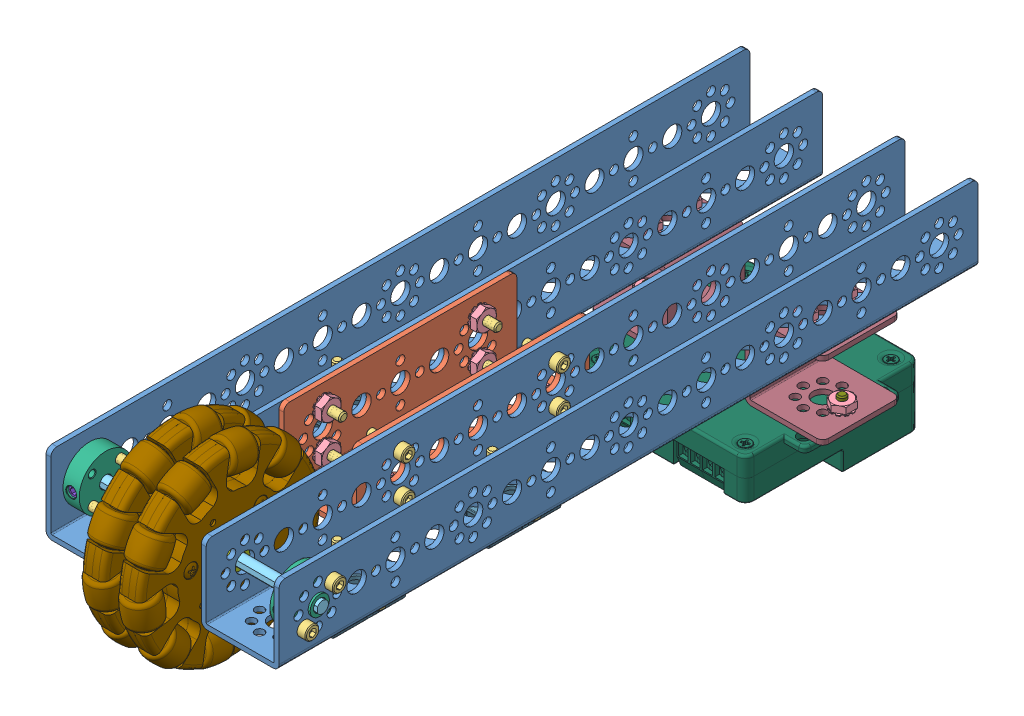
SolidWorks assembly Mantis step 4, configuration Default. Lengths in mm.
Overall size (103.01 112.11 310.85).
75 component instances, 16 part files, 198 mates.
Components (placement in the parent):
- Channel 288mm-1: Channel 288mm [Default] at (-32 0 0) size (32 32 288)
- Channel 288mm-2: Channel 288mm [Default] at (32 0 0) size (32 32 288)
- Channel 96mm-1: Channel 96mm [Default] at (0 0 32) size (32 32 96)
- Screw SHCS 6-32 x 0.5-7: Screw SHCS 6-32 x 0.5 [PreviewCfg] at (-21.5052 24 64) x (1 0 0) z (0 -1 0) size (16.21 5.74 5.74)
- Screw SHCS 6-32 x 0.5-8: Screw SHCS 6-32 x 0.5 [PreviewCfg] at (-21.5052 8 64) size (16.21 5.74 5.74)
- Screw SHCS 6-32 x 0.5-9: Screw SHCS 6-32 x 0.5 [PreviewCfg] at (-21.5052 8 0) x (1 0 0) z (0 0 -1) size (16.21 5.74 5.74)
- Screw SHCS 6-32 x 0.5-10: Screw SHCS 6-32 x 0.5 [PreviewCfg] at (-21.5052 24 0) x (1 0 0) z (0 0 -1) size (16.21 5.74 5.74)
- Nut Hex 6-32 KEP lock-1: Nut Hex 6-32 KEP lock [90675A007] at (-11.8172 8 0) x (0 0 -1) z (0 -1 0) size (8.74 3.59 9.17)
- Nut Hex 6-32 KEP lock-2: Nut Hex 6-32 KEP lock [90675A007] at (-11.8172 8 64) x (0 0 -1) z (0 -1 0) size (8.74 3.59 9.17)
- Nut Hex 6-32 KEP lock-3: Nut Hex 6-32 KEP lock [90675A007] at (-11.8172 24 64) x (0 0 -1) z (0 -1 0) size (8.74 3.59 9.17)
- Nut Hex 6-32 KEP lock-4: Nut Hex 6-32 KEP lock [90675A007] at (-11.8172 24 0) x (0 0 -1) z (0 -1 0) size (8.74 3.59 9.17)
- Screw SHCS 6-32 x 0.5-11: Screw SHCS 6-32 x 0.5 [PreviewCfg] at (21.5052 8 64) x (-1 0 0) z (0 0 -1) size (16.21 5.74 5.74)
- Screw SHCS 6-32 x 0.5-12: Screw SHCS 6-32 x 0.5 [PreviewCfg] at (21.5052 8 0) x (-1 0 0) z (0 0 -1) size (16.21 5.74 5.74)
- Screw SHCS 6-32 x 0.5-13: Screw SHCS 6-32 x 0.5 [PreviewCfg] at (21.5052 24 64) x (-1 0 0) z (0 0 -1) size (16.21 5.74 5.74)
- Screw SHCS 6-32 x 0.5-14: Screw SHCS 6-32 x 0.5 [PreviewCfg] at (21.5052 24 0) x (-1 0 0) z (0 0 -1) size (16.21 5.74 5.74)
- Nut Hex 6-32 KEP lock-5: Nut Hex 6-32 KEP lock [90675A007] at (11.8172 8 0) x (0 1 0) z (0 0 1) size (8.74 3.59 9.17)
- Nut Hex 6-32 KEP lock-6: Nut Hex 6-32 KEP lock [90675A007] at (11.8172 24 0) x (0 1 0) z (0 0 1) size (8.74 3.59 9.17)
- Nut Hex 6-32 KEP lock-7: Nut Hex 6-32 KEP lock [90675A007] at (11.8172 8 64) x (0 1 0) z (0 0 1) size (8.74 3.59 9.17)
- Nut Hex 6-32 KEP lock-8: Nut Hex 6-32 KEP lock [90675A007] at (11.8172 24 64) x (0 1 0) z (0 0 1) size (8.74 3.59 9.17)
- Axle D-shaft-1: Axle D-shaft [Default] at (0 16 128) x (0 1 0.000729) z (1 0 0) size (4.73 4.46 100)
- Hub axle shaft-1: Hub axle shaft [Default] at (46 16 128) x (0 0.707107 -0.707107) z (1 0 0) size (22 22 9.5)
- Hub axle shaft-2: Hub axle shaft [Default] at (-46 16 128) x (0 -0.707107 -0.707107) z (-1 0 0) size (22 22 9.5)
- Nylon spacer small-1: Nylon spacer small [Default] at (12.9 16 128) x (0 0 1) z (-1 0 0) size (9.5 9.5 3.1)
- Nylon spacer small-2: Nylon spacer small [Default] at (-16 16 128) x (0 0 1) z (-1 0 0) size (9.5 9.5 3.1)
- Screw SHCS 6-32 x 0.5-5: Screw SHCS 6-32 x 0.5 [PreviewCfg] at (-51.5052 10.3431 133.6569) size (16.21 5.74 5.74)
- Screw SHCS 6-32 x 0.5-4: Screw SHCS 6-32 x 0.5 [PreviewCfg] at (-51.5052 21.6569 122.3431) size (16.21 5.74 5.74)
- Screw SHCS 6-32 x 0.5-3: Screw SHCS 6-32 x 0.5 [PreviewCfg] at (51.5052 21.6569 122.3431) x (-1 0 0) z (0 0 -1) size (16.21 5.74 5.74)
- Screw SHCS 6-32 x 0.5-2: Screw SHCS 6-32 x 0.5 [PreviewCfg] at (51.5052 10.3431 133.6569) x (-1 0 0) z (0 0 -1) size (16.21 5.74 5.74)
- Screw SET 10-32 x 0.3125-2: Screw SET 10-32 x 0.3125 [PreviewCfg] at (42.6484 15.9927 138.0375) x (0 0.000729 -1) z (-1 0 0) size (7.94 4.83 4.83)
- Screw SET 10-32 x 0.3125-3: Screw SET 10-32 x 0.3125 [PreviewCfg] at (-42.6484 16.0073 138.0375) x (0 -0.000729 -1) z (1 0 0) size (7.94 4.83 4.83)
- Omni dual wheel spinner-1: Omni dual wheel spinner [Default] at (6.4355 15.7951 126.2756) x (0 0 1) z (0 -1 0) size (77.7 28.71 77.72)
  - 3-inch omni single wheel part-1: 3-inch omni single wheel part [Default] at (8.7963 -3.939 -0.2393) size (77.7 13.48 77.72)
  - Omni wheel joining hub-1: Omni wheel joining hub [Default] at (1.7244 6.4355 -0.2049) x (0.809625 0 0.586947) z (0 -1 0) size (22 22 5)
  - 3-inch omni single wheel part-2: 3-inch omni single wheel part [Default] at (8.7963 11.061 -0.2393) size (77.7 13.48 77.72)
  - Axle bronze bushing-1: Axle bronze bushing [Default] at (1.7244 -5.9645 -0.2049) x (0.809625 0 0.586947) z (0 -1 0) size (11 11 12.4)
  - Axle bronze bushing-2: Axle bronze bushing [Default] at (1.7244 18.8355 -0.2049) x (-0.809625 0 -0.586947) z (0 1 0) size (11 11 12.4)
  - Socket Button Head Cap Screw_AI-2: Socket Button Head Cap Screw_AI [SBHCSCREW 0.138-32x0.5-HX-N] at (-2.9695 20.7897 6.2733) x (0 -1 0) z (0 0 1) size (14.55 6.65 6.65)
  - Socket Button Head Cap Screw_AI-3: Socket Button Head Cap Screw_AI [SBHCSCREW 0.138-32x0.5-HX-N] at (6.4183 20.7897 -6.6831) x (0 -1 0) z (0 0 1) size (14.55 6.65 6.65)
  - Socket Button Head Cap Screw_AI-4: Socket Button Head Cap Screw_AI [SBHCSCREW 0.138-32x0.5-HX-N] at (-2.9712 -7.9187 6.2721) x (0 1 0) z (0 0 1) size (14.55 6.65 6.65)
  - Socket Button Head Cap Screw_AI-5: Socket Button Head Cap Screw_AI [SBHCSCREW 0.138-32x0.5-HX-N] at (6.42 -7.9187 -6.6819) x (0 1 0) z (0 0 1) size (14.55 6.65 6.65)
- Channel 32mm-1: Channel 32mm [Default] at (-16 -16 -96) x (0 -1 0) z (0 0 -1) size (32 32 32)
- Channel 32mm-2: Channel 32mm [Default] at (16 -16 -96) x (0 1 0) z (0 0 -1) size (32 32 32)
- Screw SHCS 6-32 x 0.5-15: Screw SHCS 6-32 x 0.5 [PreviewCfg] at (32 -5.5052 -104) x (0 1 0) z (0 0 1) size (16.21 5.74 5.74)
- Screw SHCS 6-32 x 0.5-16: Screw SHCS 6-32 x 0.5 [PreviewCfg] at (32 -5.5052 -88) x (0 1 0) z (0 0 1) size (16.21 5.74 5.74)
- Screw SHCS 6-32 x 0.5-17: Screw SHCS 6-32 x 0.5 [PreviewCfg] at (-32 -5.5052 -88) x (0 1 0) z (0 0 1) size (16.21 5.74 5.74)
- Screw SHCS 6-32 x 0.5-18: Screw SHCS 6-32 x 0.5 [PreviewCfg] at (-32 -5.5052 -104) x (0 1 0) z (0 0 1) size (16.21 5.74 5.74)
- Nut Hex 6-32 KEP lock-9: Nut Hex 6-32 KEP lock [90675A007] at (32 4.1828 -88) size (8.74 3.59 9.17)
- Nut Hex 6-32 KEP lock-10: Nut Hex 6-32 KEP lock [90675A007] at (32 4.1828 -104) x (-1 0 0) z (0 0 -1) size (8.74 3.59 9.17)
- Nut Hex 6-32 KEP lock-11: Nut Hex 6-32 KEP lock [90675A007] at (-32 4.1828 -104) size (8.74 3.59 9.17)
- Nut Hex 6-32 KEP lock-12: Nut Hex 6-32 KEP lock [90675A007] at (-32 4.1828 -88) size (8.74 3.59 9.17)
- LEGO HPC-1: LEGO HPC [Default] at (-32 0 32) x (1 0 0) z (0 0 -1) size (24.2 11.25 29.5)
- LEGO HPC-2: LEGO HPC [Default] at (32 0 32) x (1 0 0) z (0 0 -1) size (24.2 11.25 29.5)
- LEGO HPC-3: LEGO HPC [Default] at (32 0 96) x (-1 0 0) z (0 0 1) size (24.2 11.25 29.5)
- LEGO HPC-4: LEGO HPC [Default] at (-32 0 96) x (-1 0 0) z (0 0 1) size (24.2 11.25 29.5)
- Screw SHCS 6-32 x 0.5-19: Screw SHCS 6-32 x 0.5 [PreviewCfg] at (40 -4.7052 96) x (0 1 0) z (0 0 -1) size (16.21 5.74 5.74)
- Screw SHCS 6-32 x 0.5-20: Screw SHCS 6-32 x 0.5 [PreviewCfg] at (24 -4.7052 96) x (0 1 0) z (0 0 -1) size (16.21 5.74 5.74)
- Screw SHCS 6-32 x 0.5-21: Screw SHCS 6-32 x 0.5 [PreviewCfg] at (-24 -4.7052 96) x (0 1 0) z (0 0 -1) size (16.21 5.74 5.74)
- Screw SHCS 6-32 x 0.5-22: Screw SHCS 6-32 x 0.5 [PreviewCfg] at (-40 -4.7052 96) x (0 1 0) z (0 0 -1) size (16.21 5.74 5.74)
- Screw SHCS 6-32 x 0.5-23: Screw SHCS 6-32 x 0.5 [PreviewCfg] at (24 -4.7052 32) x (0 1 0) z (0 0 1) size (16.21 5.74 5.74)
- Screw SHCS 6-32 x 0.5-24: Screw SHCS 6-32 x 0.5 [PreviewCfg] at (40 -4.7052 32) x (0 1 0) z (0 0 -1) size (16.21 5.74 5.74)
- Screw SHCS 6-32 x 0.5-25: Screw SHCS 6-32 x 0.5 [PreviewCfg] at (-24 -4.7052 32) x (0 1 0) z (0 0 1) size (16.21 5.74 5.74)
- Screw SHCS 6-32 x 0.5-26: Screw SHCS 6-32 x 0.5 [PreviewCfg] at (-40 -4.7052 32) x (0 1 0) z (0 0 1) size (16.21 5.74 5.74)
- Nut Hex 6-32 KEP lock-13: Nut Hex 6-32 KEP lock [90675A007] at (40 4.1828 96) size (8.74 3.59 9.17)
- Nut Hex 6-32 KEP lock-14: Nut Hex 6-32 KEP lock [90675A007] at (40 4.1828 32) x (-1 0 0) z (0 0 -1) size (8.74 3.59 9.17)
- Nut Hex 6-32 KEP lock-15: Nut Hex 6-32 KEP lock [90675A007] at (24 4.1828 32) size (8.74 3.59 9.17)
- Nut Hex 6-32 KEP lock-16: Nut Hex 6-32 KEP lock [90675A007] at (24 4.1828 96) size (8.74 3.59 9.17)
- Nut Hex 6-32 KEP lock-17: Nut Hex 6-32 KEP lock [90675A007] at (-24 4.1828 96) x (-1 0 0) z (0 0 -1) size (8.74 3.59 9.17)
- Nut Hex 6-32 KEP lock-18: Nut Hex 6-32 KEP lock [90675A007] at (-40 4.1828 96) size (8.74 3.59 9.17)
- Nut Hex 6-32 KEP lock-19: Nut Hex 6-32 KEP lock [90675A007] at (-24 4.1828 32) size (8.74 3.59 9.17)
- Nut Hex 6-32 KEP lock-20: Nut Hex 6-32 KEP lock [90675A007] at (-40 4.1828 32) size (8.74 3.59 9.17)
- Tetrix DC Control-1: Tetrix DC Control [Default] at (-6.8932 -42.476 -98.2492) x (-1 0 0) z (0 0 1) size (89 25.25 72)
- Screw BHCS 6-32 x 0.375-1: Screw BHCS 6-32 x 0.375 [PreviewCfg] at (-40 -36.2542 -96) x (0 1 0) z (0 0 -1) size (11.38 6.65 6.65)
- Screw BHCS 6-32 x 0.375-2: Screw BHCS 6-32 x 0.375 [PreviewCfg] at (40 -36.2542 -96) x (0 1 0) z (0 0 -1) size (11.38 6.65 6.65)
- Nut Hex 6-32 KEP lock-21: Nut Hex 6-32 KEP lock [90675A007] at (-40 -27.8172 -96) x (-1 0 0) z (0 0 -1) size (8.74 3.59 9.17)
- Nut Hex 6-32 KEP lock-22: Nut Hex 6-32 KEP lock [90675A007] at (40 -27.8172 -96) size (8.74 3.59 9.17)
Mates (geometry in assembly coordinates):
- Concentric7: concentric anti-aligned: cylinder of Screw SHCS 6-32 x 0.5-3 through (83.2552 21.6569 122.3431) axis (1 0 0) radius 1.7526; cylinder of Channel 288mm-2 through (48 21.6569 122.3431) axis (-1 0 0) radius 1.85
- Coincident6: coincident anti-aligned: plane of Channel 288mm-2 through (48 2.5 144) normal (1 0 0); plane of Screw SHCS 6-32 x 0.5-3 through (48 24.5271 122.3431) normal (-1 0 0)
- Concentric8: concentric anti-aligned: cylinder of Screw SHCS 6-32 x 0.5-2 through (83.2552 10.3431 133.6569) axis (1 0 0) radius 1.7526; cylinder of Channel 288mm-2 through (48 10.3431 133.6569) axis (-1 0 0) radius 1.85
- Coincident7: coincident anti-aligned: plane of Channel 288mm-2 through (48 2.5 144) normal (1 0 0); plane of Screw SHCS 6-32 x 0.5-2 through (48 13.2133 133.6569) normal (-1 0 0)
- Concentric10: concentric aligned: cylinder of Screw SHCS 6-32 x 0.5-4 through (-83.2552 21.6569 122.3431) axis (-1 0 0) radius 1.7526; cylinder of Channel 288mm-1 through (-16 21.6569 122.3431) axis (-1 0 0) radius 1.85
- Coincident8: coincident anti-aligned: plane of Channel 288mm-1 through (-48 32 144) normal (-1 0 0); plane of Screw SHCS 6-32 x 0.5-4 through (-48 24.5271 122.3431) normal (1 0 0)
- Concentric11: concentric aligned: cylinder of Screw SHCS 6-32 x 0.5-5 through (-83.2552 10.3431 133.6569) axis (-1 0 0) radius 1.7526; cylinder of Channel 288mm-1 through (-16 10.3431 133.6569) axis (-1 0 0) radius 1.85
- Coincident9: coincident anti-aligned: plane of Channel 288mm-1 through (-48 32 144) normal (-1 0 0); plane of Screw SHCS 6-32 x 0.5-5 through (-48 13.2133 133.6569) normal (1 0 0)
- Concentric15: concentric aligned: cylinder of Screw SHCS 6-32 x 0.5-8 through (-53.2552 8 64) axis (-1 0 0) radius 1.7526; cylinder of Channel 96mm-1 through (16 8 64) axis (-1 0 0) radius 1.85
- Concentric16: concentric aligned: cylinder of Screw SHCS 6-32 x 0.5-10 through (-53.2552 24 0) axis (-1 0 0) radius 1.7526; cylinder of Channel 96mm-1 through (16 24 0) axis (-1 0 0) radius 1.85
- Coincident11: coincident anti-aligned: plane of Channel 288mm-1 through (-18 32 144) normal (-1 0 0); plane of Screw SHCS 6-32 x 0.5-10 through (-18 21.1298 0) normal (1 0 0)
- Coincident12: coincident anti-aligned: plane of Channel 288mm-1 through (-18 32 144) normal (-1 0 0); plane of Screw SHCS 6-32 x 0.5-8 through (-18 10.8702 64) normal (1 0 0)
- Concentric17: concentric aligned: cylinder of Screw SHCS 6-32 x 0.5-7 through (-53.2552 24 64) axis (-1 0 0) radius 1.7526; cylinder of Channel 96mm-1 through (16 24 64) axis (-1 0 0) radius 1.85
- Concentric18: concentric aligned: cylinder of Screw SHCS 6-32 x 0.5-9 through (-53.2552 8 0) axis (-1 0 0) radius 1.7526; cylinder of Channel 96mm-1 through (16 8 0) axis (-1 0 0) radius 1.85
- Coincident13: coincident anti-aligned: plane of Channel 288mm-1 through (-18 32 144) normal (-1 0 0); plane of Screw SHCS 6-32 x 0.5-9 through (-18 5.1298 0) normal (1 0 0)
- Coincident14: coincident anti-aligned: plane of Channel 288mm-1 through (-18 32 144) normal (-1 0 0); plane of Screw SHCS 6-32 x 0.5-7 through (-18 24 66.8702) normal (1 0 0)
- Concentric19: concentric anti-aligned: cylinder of Screw SHCS 6-32 x 0.5-9 through (-53.2552 8 0) axis (-1 0 0) radius 1.7526; circle of Nut Hex 6-32 KEP lock-1
- Concentric20: concentric anti-aligned: cylinder of Screw SHCS 6-32 x 0.5-7 through (-53.2552 24 64) axis (-1 0 0) radius 1.7526; circle of Nut Hex 6-32 KEP lock-3
- Concentric21: concentric anti-aligned: cylinder of Screw SHCS 6-32 x 0.5-8 through (-53.2552 8 64) axis (-1 0 0) radius 1.7526; circle of Nut Hex 6-32 KEP lock-2
- Coincident16: coincident: plane of Channel 96mm-1 through (-14 2.5 80) normal (1 0 0); moEndPointRef_w of Nut Hex 6-32 KEP lock-4
- Coincident17: coincident aligned: plane of Channel 96mm-1 through (-14 2.5 80) normal (1 0 0); circle of Nut Hex 6-32 KEP lock-2
- Coincident18: coincident aligned: plane of Channel 96mm-1 through (-14 2.5 80) normal (1 0 0); circle of Nut Hex 6-32 KEP lock-1
- Coincident19: coincident aligned: plane of Channel 96mm-1 through (-14 2.5 80) normal (1 0 0); circle of Nut Hex 6-32 KEP lock-3
- Concentric29: concentric anti-aligned: cylinder of Screw SHCS 6-32 x 0.5-13 through (53.2552 24 64) axis (1 0 0) radius 1.7526; cylinder of Channel 96mm-1 through (16 24 64) axis (-1 0 0) radius 1.85
- Concentric30: concentric anti-aligned: cylinder of Screw SHCS 6-32 x 0.5-11 through (53.2552 8 64) axis (1 0 0) radius 1.7526; cylinder of Channel 96mm-1 through (16 8 64) axis (-1 0 0) radius 1.85
- Concentric31: concentric anti-aligned: cylinder of Screw SHCS 6-32 x 0.5-12 through (53.2552 8 0) axis (1 0 0) radius 1.7526; cylinder of Channel 96mm-1 through (16 8 0) axis (-1 0 0) radius 1.85
- Concentric32: concentric anti-aligned: cylinder of Screw SHCS 6-32 x 0.5-14 through (53.2552 24 0) axis (1 0 0) radius 1.7526; cylinder of Channel 96mm-1 through (16 24 0) axis (-1 0 0) radius 1.85
- Coincident25: coincident anti-aligned: plane of Channel 288mm-2 through (18 2.5 144) normal (1 0 0); plane of Screw SHCS 6-32 x 0.5-12 through (18 10.8702 0) normal (-1 0 0)
- Coincident26: coincident anti-aligned: plane of Channel 288mm-2 through (18 2.5 144) normal (1 0 0); plane of Screw SHCS 6-32 x 0.5-14 through (18 26.8702 0) normal (-1 0 0)
- Coincident27: coincident anti-aligned: plane of Channel 288mm-2 through (18 2.5 144) normal (1 0 0); plane of Screw SHCS 6-32 x 0.5-13 through (18 26.8702 64) normal (-1 0 0)
- Coincident28: coincident anti-aligned: plane of Channel 288mm-2 through (18 2.5 144) normal (1 0 0); plane of Screw SHCS 6-32 x 0.5-11 through (18 10.8702 64) normal (-1 0 0)
- Concentric33: concentric anti-aligned: cylinder of Screw SHCS 6-32 x 0.5-13 through (53.2552 24 64) axis (1 0 0) radius 1.7526; circle of Nut Hex 6-32 KEP lock-8
- Concentric34: concentric anti-aligned: cylinder of Screw SHCS 6-32 x 0.5-11 through (53.2552 8 64) axis (1 0 0) radius 1.7526; circle of Nut Hex 6-32 KEP lock-7
- Concentric35: concentric anti-aligned: cylinder of Screw SHCS 6-32 x 0.5-12 through (53.2552 8 0) axis (1 0 0) radius 1.7526; circle of Nut Hex 6-32 KEP lock-5
- Concentric36: concentric anti-aligned: cylinder of Screw SHCS 6-32 x 0.5-14 through (53.2552 24 0) axis (1 0 0) radius 1.7526; circle of Nut Hex 6-32 KEP lock-6
- Coincident29: coincident aligned: plane of Channel 96mm-1 through (14 32 80) normal (-1 0 0); circle of Nut Hex 6-32 KEP lock-5
- Coincident30: coincident aligned: plane of Channel 96mm-1 through (14 32 80) normal (-1 0 0); circle of Nut Hex 6-32 KEP lock-6
- Coincident31: coincident: plane of Channel 96mm-1 through (14 32 80) normal (-1 0 0); moEndPointRef_w of Nut Hex 6-32 KEP lock-8
- Coincident32: coincident aligned: plane of Channel 96mm-1 through (14 32 80) normal (-1 0 0); circle of Nut Hex 6-32 KEP lock-7
- Concentric37: concentric anti-aligned: circle of LEGO HPC-1; cylinder of Channel 288mm-1 through (-32 32 32) axis (0 -1 0) radius 4
- Coincident33: coincident anti-aligned: plane of Channel 288mm-1 through (-45.5 0 144) normal (0 -1 0); plane of LEGO HPC-1 through (-32 0 32) normal (0 1 0)
- Concentric39: concentric anti-aligned: cylinder of LEGO HPC-2 through (32 -10.5 32) axis (0 1 0) radius 3.1; cylinder of Channel 288mm-2 through (32 32 32) axis (0 -1 0) radius 4
- Coincident34: coincident anti-aligned: plane of Channel 288mm-2 through (18.5 0 144) normal (0 -1 0); plane of LEGO HPC-2 through (32 0 32) normal (0 1 0)
- Concentric41: concentric anti-aligned: cylinder of LEGO HPC-3 through (32 -10.5 96) axis (0 1 0) radius 3.1; cylinder of Channel 288mm-2 through (32 32 96) axis (0 -1 0) radius 4
- Concentric43: concentric anti-aligned: cylinder of LEGO HPC-4 through (-32 -10.5 96) axis (0 1 0) radius 3.1; cylinder of Channel 288mm-1 through (-32 32 96) axis (0 -1 0) radius 4
- Coincident36: coincident anti-aligned: plane of Channel 288mm-1 through (-45.5 0 144) normal (0 -1 0); plane of LEGO HPC-4 through (-32 0 96) normal (0 1 0)
- Concentric45: concentric anti-aligned: cylinder of Channel 32mm-1 through (-32 -32 -96) axis (0 1 0) radius 4; cylinder of Channel 288mm-1 through (-32 32 -96) axis (0 -1 0) radius 4
- Coincident37: coincident anti-aligned: plane of Channel 288mm-1 through (-45.5 0 144) normal (0 -1 0); plane of Channel 32mm-1 through (-48 0 -112) normal (0 1 0)
- Parallel28: parallel anti-aligned: plane of Channel 32mm-1; plane of assembly through (0 0 0) normal (1 0 0)
- Concentric47: concentric aligned: cylinder of Channel 32mm-2 through (32 0 -96) axis (0 -1 0) radius 4; cylinder of Channel 288mm-2 through (32 32 -96) axis (0 -1 0) radius 4
- Coincident38: coincident anti-aligned: plane of Channel 288mm-2 through (18.5 0 144) normal (0 -1 0); plane of Channel 32mm-2 through (18.5 0 -112) normal (0 1 0)
- Parallel29: parallel aligned: plane of Channel 32mm-2; plane of assembly through (0 0 0) normal (1 0 0)
- Concentric48: concentric anti-aligned: cylinder of Screw SHCS 6-32 x 0.5-18 through (-32 -37.2552 -104) axis (0 -1 0) radius 1.7526; cylinder of Channel 32mm-1 through (-32 -32 -104) axis (0 1 0) radius 1.85
- Concentric49: concentric anti-aligned: cylinder of Screw SHCS 6-32 x 0.5-17 through (-32 -37.2552 -88) axis (0 -1 0) radius 1.7526; cylinder of Channel 32mm-1 through (-32 -32 -88) axis (0 1 0) radius 1.85
- Coincident39: coincident anti-aligned: plane of Channel 32mm-1 through (-18.5 -2 -112) normal (0 -1 0); plane of Screw SHCS 6-32 x 0.5-18 through (-34.8702 -2 -104) normal (0 1 0)
- Coincident40: coincident anti-aligned: plane of Channel 32mm-1 through (-18.5 -2 -112) normal (0 -1 0); plane of Screw SHCS 6-32 x 0.5-17 through (-34.8702 -2 -88) normal (0 1 0)
- Concentric50: concentric aligned: cylinder of Screw SHCS 6-32 x 0.5-15 through (32 -37.2552 -104) axis (0 -1 0) radius 1.7526; cylinder of Channel 32mm-2 through (32 0 -104) axis (0 -1 0) radius 1.85
- Concentric51: concentric aligned: cylinder of Screw SHCS 6-32 x 0.5-16 through (32 -37.2552 -88) axis (0 -1 0) radius 1.7526; cylinder of Channel 32mm-2 through (32 0 -88) axis (0 -1 0) radius 1.85
- Coincident41: coincident anti-aligned: plane of Channel 32mm-2 through (48 -2 -112) normal (0 -1 0); plane of Screw SHCS 6-32 x 0.5-15 through (29.1298 -2 -104) normal (0 1 0)
- Coincident43: coincident anti-aligned: plane of Channel 32mm-2 through (48 -2 -112) normal (0 -1 0); plane of Screw SHCS 6-32 x 0.5-16 through (29.1298 -2 -88) normal (0 1 0)
- Concentric54: concentric anti-aligned: cylinder of Screw SHCS 6-32 x 0.5-18 through (-32 -37.2552 -104) axis (0 -1 0) radius 1.7526; circle of Nut Hex 6-32 KEP lock-11
- Concentric55: concentric anti-aligned: cylinder of Screw SHCS 6-32 x 0.5-17 through (-32 -37.2552 -88) axis (0 -1 0) radius 1.7526; circle of Nut Hex 6-32 KEP lock-12
- Concentric56: concentric anti-aligned: cylinder of Screw SHCS 6-32 x 0.5-16 through (32 -37.2552 -88) axis (0 -1 0) radius 1.7526; circle of Nut Hex 6-32 KEP lock-9
- Concentric57: concentric anti-aligned: cylinder of Screw SHCS 6-32 x 0.5-15 through (32 -37.2552 -104) axis (0 -1 0) radius 1.7526; circle of Nut Hex 6-32 KEP lock-10
- Coincident44: coincident: plane of Channel 288mm-2 through (45.5 2 144) normal (0 1 0); moEndPointRef_w of Nut Hex 6-32 KEP lock-10
- Coincident45: coincident aligned: plane of Channel 288mm-2 through (45.5 2 144) normal (0 1 0); circle of Nut Hex 6-32 KEP lock-9
- Coincident46: coincident aligned: plane of Channel 288mm-1 through (-18.5 2 144) normal (0 1 0); circle of Nut Hex 6-32 KEP lock-11
- Coincident47: coincident aligned: plane of Channel 288mm-1 through (-18.5 2 144) normal (0 1 0); circle of Nut Hex 6-32 KEP lock-12
- Concentric63: concentric aligned: cylinder of Screw SHCS 6-32 x 0.5-19 through (40 -36.4552 96) axis (0 -1 0) radius 1.7526; cylinder of Channel 288mm-2 through (40 32 96) axis (0 -1 0) radius 1.85
- Coincident48: coincident anti-aligned: plane of LEGO HPC-1 through (-32 -1.2 32) normal (0 -1 0); plane of Screw SHCS 6-32 x 0.5-22 through (-37.1298 -1.2 96) normal (0 1 0)
- Coincident49: coincident anti-aligned: plane of LEGO HPC-1 through (-32 -1.2 32) normal (0 -1 0); plane of Screw SHCS 6-32 x 0.5-21 through (-21.1298 -1.2 96) normal (0 1 0)
- Coincident50: coincident anti-aligned: plane of LEGO HPC-4 through (-32 -1.2 96) normal (0 -1 0); plane of Screw SHCS 6-32 x 0.5-25 through (-26.8702 -1.2 32) normal (0 1 0)
- Coincident51: coincident anti-aligned: plane of LEGO HPC-4 through (-32 -1.2 96) normal (0 -1 0); plane of Screw SHCS 6-32 x 0.5-26 through (-42.8702 -1.2 32) normal (0 1 0)
- Coincident52: coincident anti-aligned: plane of LEGO HPC-3 through (32 -1.2 96) normal (0 -1 0); plane of Screw SHCS 6-32 x 0.5-23 through (21.1298 -1.2 32) normal (0 1 0)
- Coincident53: coincident anti-aligned: plane of LEGO HPC-3 through (32 -1.2 96) normal (0 -1 0); plane of Screw SHCS 6-32 x 0.5-24 through (42.8702 -1.2 32) normal (0 1 0)
- Coincident54: coincident anti-aligned: plane of LEGO HPC-2 through (32 -1.2 32) normal (0 -1 0); plane of Screw SHCS 6-32 x 0.5-19 through (42.8702 -1.2 96) normal (0 1 0)
- Coincident55: coincident anti-aligned: plane of LEGO HPC-2 through (32 -1.2 32) normal (0 -1 0); plane of Screw SHCS 6-32 x 0.5-20 through (26.8702 -1.2 96) normal (0 1 0)
- Concentric66: concentric anti-aligned: cylinder of Screw SHCS 6-32 x 0.5-26 through (-40 -36.4552 32) axis (0 -1 0) radius 1.7526; circle of Nut Hex 6-32 KEP lock-20
- Concentric67: concentric anti-aligned: cylinder of Screw SHCS 6-32 x 0.5-25 through (-24 -36.4552 32) axis (0 -1 0) radius 1.7526; circle of Nut Hex 6-32 KEP lock-19
- Concentric68: concentric anti-aligned: cylinder of Screw SHCS 6-32 x 0.5-22 through (-40 -36.4552 96) axis (0 -1 0) radius 1.7526; circle of Nut Hex 6-32 KEP lock-18
- Concentric69: concentric anti-aligned: cylinder of Screw SHCS 6-32 x 0.5-21 through (-24 -36.4552 96) axis (0 -1 0) radius 1.7526; circle of Nut Hex 6-32 KEP lock-17
- Concentric70: concentric anti-aligned: circle of Screw SHCS 6-32 x 0.5-20; circle of Nut Hex 6-32 KEP lock-16
- Concentric71: concentric anti-aligned: cylinder of Screw SHCS 6-32 x 0.5-19 through (40 -36.4552 96) axis (0 -1 0) radius 1.7526; circle of Nut Hex 6-32 KEP lock-13
- Concentric72: concentric anti-aligned: cylinder of Screw SHCS 6-32 x 0.5-24 through (40 -36.4552 32) axis (0 -1 0) radius 1.7526; circle of Nut Hex 6-32 KEP lock-14
- Concentric73: concentric anti-aligned: cylinder of Screw SHCS 6-32 x 0.5-23 through (24 -36.4552 32) axis (0 -1 0) radius 1.7526; circle of Nut Hex 6-32 KEP lock-15
- Coincident63: coincident aligned: plane of Nut Hex 6-32 KEP lock-13 through (40 2 96) normal (0 1 0); plane of Channel 288mm-2 through (45.5 2 144) normal (0 1 0)
- Concentric74: concentric anti-aligned: cylinder of Tetrix DC Control-1 through (-40 -32 -96) axis (0 -1 0) radius 2.425; cylinder of Channel 32mm-1 through (-40 -32 -96) axis (0 1 0) radius 1.85
- Coincident64: coincident anti-aligned: plane of Channel 32mm-1 through (-18.5 -32 -112) normal (0 -1 0); plane of Tetrix DC Control-1 through (-32.3614 -32 -128.5) normal (0 1 0)
- Parallel3: parallel anti-aligned: plane of Tetrix DC Control-1; plane of assembly through (0 0 0) normal (1 0 0)
- Concentric80: concentric aligned: cylinder of Hub axle shaft-1 through (48.8 16 128) axis (-1 0 0) radius 3.9624; cylinder of Channel 288mm-2 through (48 16 128) axis (-1 0 0) radius 4
- Coincident70: coincident anti-aligned: plane of Channel 288mm-2 through (46 32 144) normal (-1 0 0); plane of Hub axle shaft-1 through (46 16 128) normal (1 0 0)
- Concentric82: concentric aligned: cylinder of Screw SET 10-32 x 0.3125-2 through (42.6484 15.9834 150.7375) axis (0 -0.000729 1) radius 2.413; cylinder of Hub axle shaft-1 through (42.6484 15.992 139) axis (0 -0.000729 1) radius 2.0193
- Concentric83: concentric aligned: cylinder of Hub axle shaft-2 through (-39.3 16 128) axis (-1 0 0) radius 2.3495; cylinder of Channel 288mm-1 through (-16 16 128) axis (-1 0 0) radius 4
- Coincident71: coincident anti-aligned: plane of Channel 288mm-1 through (-46 2.5 144) normal (1 0 0); plane of Hub axle shaft-2 through (-46 16 128) normal (-1 0 0)
- Concentric84: concentric aligned: cylinder of Screw SET 10-32 x 0.3125-3 through (-42.6484 16.0166 150.7375) axis (0 0.000729 1) radius 2.413; cylinder of Hub axle shaft-2 through (-42.6484 16.008 139) axis (0 0.000729 1) radius 2.0193
- Concentric85: concentric anti-aligned: cylinder of Axle D-shaft-1 through (-50 16 128) axis (1 0 0) radius 2.365; cylinder of Channel 288mm-1 through (-16 16 128) axis (-1 0 0) radius 4
- Concentric86: concentric anti-aligned: cylinder of Axle D-shaft-1 through (-50 16 128) axis (1 0 0) radius 2.365; cylinder of Nylon spacer small-1 through (16 16 128) axis (-1 0 0) radius 2.5
- Concentric87: concentric anti-aligned: cylinder of Axle D-shaft-1 through (-50 16 128) axis (1 0 0) radius 2.365; cylinder of Nylon spacer small-2 through (-12.9 16 128) axis (-1 0 0) radius 2.5
- Coincident72: coincident anti-aligned: plane of Channel 288mm-2 through (16 32 144) normal (-1 0 0); plane of Nylon spacer small-1 through (16 16 128) normal (1 0 0)
- Coincident73: coincident anti-aligned: plane of Channel 288mm-1 through (-16 2.5 144) normal (1 0 0); plane of Nylon spacer small-2 through (-16 16 128) normal (-1 0 0)
- Coincident74: coincident aligned: plane of Channel 288mm-1 through (-32 0 0) normal (0 0 1); plane of Channel 288mm-2 through (32 0 0) normal (0 0 1)
- Coincident75: coincident aligned: plane of Channel 288mm-1 through (-32 0 0) normal (0 1 0); plane of Channel 288mm-2 through (32 0 0) normal (0 1 0)
- Coincident76: coincident anti-aligned: plane of Channel 288mm-1 through (-16 2.5 144) normal (1 0 0); plane of Channel 96mm-1 through (-16 32 80) normal (-1 0 0)
- Coincident77: coincident anti-aligned: plane of Channel 288mm-2 through (16 32 144) normal (-1 0 0); plane of Channel 96mm-1 through (16 2.5 80) normal (1 0 0)
- Coincident78: coincident aligned: plane of Channel 288mm-1 through (-32 0 0) normal (0 1 0); plane of Channel 96mm-1 through (0 0 32) normal (0 1 0)
- Concentric88: concentric aligned: cylinder of Channel 288mm-2 through (48 16 32) axis (-1 0 0) radius 4; cylinder of Channel 96mm-1 through (16 16 32) axis (-1 0 0) radius 4
- Coincident79: coincident aligned: plane of Channel 96mm-1 through (0 0 32) normal (1 0 0); plane of assembly through (0 0 0) normal (1 0 0)
- Coincident80: coincident aligned: plane of Channel 288mm-1 through (-32 0 0) normal (0 0 1); plane of assembly through (0 0 0) normal (0 0 1)
- Coincident81: coincident aligned: plane of Channel 288mm-1 through (-32 0 0) normal (0 1 0); plane of assembly through (0 0 0) normal (0 1 0)
- Parallel4: parallel anti-aligned: plane of Channel 96mm-1 through (0 0 32) normal (0 1 0); plane of Screw SHCS 6-32 x 0.5-7 through (-21.5052 24 64) normal (0 -1 0)
- Parallel5: parallel aligned: plane of Channel 96mm-1 through (0 0 32) normal (0 0 1); plane of Screw SHCS 6-32 x 0.5-8 through (-21.5052 8 64) normal (0 0 1)
- Parallel6: parallel anti-aligned: plane of Screw SHCS 6-32 x 0.5-9 through (-21.5052 8 0) normal (0 0 -1); plane of Channel 96mm-1 through (0 0 32) normal (0 0 1)
- Parallel7: parallel anti-aligned: plane of Channel 96mm-1 through (0 0 32) normal (0 0 1); plane of Screw SHCS 6-32 x 0.5-10 through (-21.5052 24 0) normal (0 0 -1)
- Coincident84: coincident anti-aligned: axis of Screw SHCS 6-32 x 0.5-10 through (-5.7724 24 0) axis (-1 0 0); axis of Nut Hex 6-32 KEP lock-4 through (-11.2622 24 0) axis (1 0 0)
- Parallel8: parallel anti-aligned: plane of Channel 96mm-1 through (0 0 32) normal (0 1 0); plane of Nut Hex 6-32 KEP lock-3 through (-11.8172 24 64) normal (0 -1 0)
- Parallel9: parallel anti-aligned: plane of Channel 96mm-1 through (0 0 32) normal (0 1 0); plane of Nut Hex 6-32 KEP lock-2 through (-11.8172 8 64) normal (0 -1 0)
- Parallel10: parallel anti-aligned: plane of Channel 96mm-1 through (0 0 32) normal (0 1 0); plane of Nut Hex 6-32 KEP lock-1 through (-11.8172 8 0) normal (0 -1 0)
- Parallel11: parallel anti-aligned: plane of Channel 96mm-1 through (0 0 32) normal (0 1 0); plane of Nut Hex 6-32 KEP lock-4 through (-11.8172 24 0) normal (0 -1 0)
- Parallel12: parallel anti-aligned: plane of Channel 96mm-1 through (0 0 32) normal (0 0 1); plane of Screw SHCS 6-32 x 0.5-11 through (21.5052 8 64) normal (0 0 -1)
- Parallel13: parallel anti-aligned: plane of Channel 96mm-1 through (0 0 32) normal (0 0 1); plane of Screw SHCS 6-32 x 0.5-12 through (21.5052 8 0) normal (0 0 -1)
- Parallel14: parallel anti-aligned: plane of Channel 96mm-1 through (0 0 32) normal (0 0 1); plane of Screw SHCS 6-32 x 0.5-13 through (21.5052 24 64) normal (0 0 -1)
- Parallel15: parallel anti-aligned: plane of Channel 96mm-1 through (0 0 32) normal (0 0 1); plane of Screw SHCS 6-32 x 0.5-14 through (21.5052 24 0) normal (0 0 -1)
- Parallel16: parallel aligned: plane of Channel 96mm-1 through (0 0 32) normal (0 0 1); plane of Nut Hex 6-32 KEP lock-5 through (11.8172 8 0) normal (0 0 1)
- Parallel17: parallel aligned: plane of Channel 96mm-1 through (0 0 32) normal (0 0 1); plane of Nut Hex 6-32 KEP lock-6 through (11.8172 24 0) normal (0 0 1)
- Parallel18: parallel aligned: plane of Channel 96mm-1 through (0 0 32) normal (0 0 1); plane of Nut Hex 6-32 KEP lock-7 through (11.8172 8 64) normal (0 0 1)
- Parallel19: parallel aligned: plane of Channel 96mm-1 through (0 0 32) normal (0 0 1); plane of Nut Hex 6-32 KEP lock-8 through (11.8172 24 64) normal (0 0 1)
- Concentric89: concentric aligned: cylinder of Hub axle shaft-2 through (-46 21.6569 122.3431) axis (-1 0 0) radius 1.3526; cylinder of Screw SHCS 6-32 x 0.5-4 through (-83.2552 21.6569 122.3431) axis (-1 0 0) radius 1.7526
- Concentric90: concentric aligned: cylinder of Hub axle shaft-1 through (46 21.6569 122.3431) axis (1 0 0) radius 1.3526; cylinder of Screw SHCS 6-32 x 0.5-3 through (83.2552 21.6569 122.3431) axis (1 0 0) radius 1.7526
- Perpendicular1: perpendicular: plane of Axle D-shaft-1 through (-50 14.9107 130.0992) normal (0 -0.000729 1); axis of Hub axle shaft-1 through (42.6484 15.9991 129.2011) axis (0 -0.000729 1)
- Coincident93: coincident aligned: plane of Axle D-shaft-1 through (0 16 128) normal (1 0 0); plane of assembly through (0 0 0) normal (1 0 0)
- Parallel20: parallel aligned: plane of assembly through (0 0 0) normal (0 0 1); plane of Nylon spacer small-1 through (12.9 16 128) normal (0 0 1)
- Parallel21: parallel aligned: plane of assembly through (0 0 0) normal (0 0 1); plane of Nylon spacer small-2 through (-16 16 128) normal (0 0 1)
- Parallel22: parallel anti-aligned: plane of Screw SET 10-32 x 0.3125-2 through (42.6484 15.9927 138.0375) normal (-1 0 0); plane of assembly through (0 0 0) normal (1 0 0)
- Coincident95: coincident aligned: plane of Axle D-shaft-1 through (-50 14.9107 130.0992) normal (0 -0.000729 1); circle of Screw SET 10-32 x 0.3125-2
- Parallel23: parallel aligned: plane of Screw SET 10-32 x 0.3125-3 through (-42.6484 16.0073 138.0375) normal (1 0 0); plane of assembly through (0 0 0) normal (1 0 0)
- Coincident103: coincident: plane of Axle D-shaft-1 through (-50 14.9107 130.0992) normal (0 -0.000729 1); point of Screw SET 10-32 x 0.3125-3
- Parallel24: parallel aligned: plane of assembly through (0 0 0) normal (0 0 1); plane of Screw SHCS 6-32 x 0.5-5 through (-51.5052 10.3431 133.6569) normal (0 0 1)
- Parallel25: parallel aligned: plane of assembly through (0 0 0) normal (0 0 1); plane of Screw SHCS 6-32 x 0.5-4 through (-51.5052 21.6569 122.3431) normal (0 0 1)
- Parallel26: parallel anti-aligned: plane of assembly through (0 0 0) normal (0 0 1); plane of Screw SHCS 6-32 x 0.5-3 through (51.5052 21.6569 122.3431) normal (0 0 -1)
- Parallel27: parallel anti-aligned: plane of assembly through (0 0 0) normal (0 0 1); plane of Screw SHCS 6-32 x 0.5-2 through (51.5052 10.3431 133.6569) normal (0 0 -1)
- Parallel30: parallel aligned: plane of assembly through (0 0 0) normal (0 0 1); plane of Nut Hex 6-32 KEP lock-12 through (-32 4.1828 -88) normal (0 0 1)
- Parallel31: parallel aligned: plane of assembly through (0 0 0) normal (0 0 1); plane of Nut Hex 6-32 KEP lock-11 through (-32 4.1828 -104) normal (0 0 1)
- Parallel32: parallel anti-aligned: plane of assembly through (0 0 0) normal (0 0 1); plane of Nut Hex 6-32 KEP lock-10 through (32 4.1828 -104) normal (0 0 -1)
- Parallel33: parallel aligned: plane of assembly through (0 0 0) normal (0 0 1); plane of Nut Hex 6-32 KEP lock-9 through (32 4.1828 -88) normal (0 0 1)
- Parallel34: parallel aligned: plane of assembly through (0 0 0) normal (0 0 1); plane of Screw SHCS 6-32 x 0.5-18 through (-32 -5.5052 -104) normal (0 0 1)
- Parallel35: parallel aligned: plane of assembly through (0 0 0) normal (0 0 1); plane of Screw SHCS 6-32 x 0.5-17 through (-32 -5.5052 -88) normal (0 0 1)
- Parallel36: parallel aligned: plane of assembly through (0 0 0) normal (0 0 1); plane of Screw SHCS 6-32 x 0.5-16 through (32 -5.5052 -88) normal (0 0 1)
- Parallel37: parallel aligned: plane of assembly through (0 0 0) normal (0 0 1); plane of Screw SHCS 6-32 x 0.5-15 through (32 -5.5052 -104) normal (0 0 1)
- Parallel38: parallel anti-aligned: plane of LEGO HPC-1 through (-32 0 32) normal (0 0 -1); plane of assembly through (0 0 0) normal (0 0 1)
- Parallel39: parallel anti-aligned: plane of LEGO HPC-2 through (32 0 32) normal (0 0 -1); plane of assembly through (0 0 0) normal (0 0 1)
- Coincident116: coincident anti-aligned: plane of Channel 288mm-2 through (18.5 0 144) normal (0 -1 0); plane of LEGO HPC-3 through (32 0 96) normal (0 1 0)
- Parallel40: parallel aligned: plane of assembly through (0 0 0) normal (0 0 1); plane of LEGO HPC-3 through (32 0 96) normal (0 0 1)
- Parallel41: parallel aligned: plane of assembly through (0 0 0) normal (0 0 1); plane of LEGO HPC-4 through (-32 0 96) normal (0 0 1)
- Concentric91: concentric aligned: cylinder of Channel 288mm-2 through (24 32 96) axis (0 -1 0) radius 1.85; cylinder of Screw SHCS 6-32 x 0.5-20 through (24 -36.4552 96) axis (0 -1 0) radius 1.7526
- Coincident117: coincident aligned: plane of Channel 288mm-2 through (45.5 2 144) normal (0 1 0); plane of Nut Hex 6-32 KEP lock-16 through (24 2 96) normal (0 1 0)
- Coincident118: coincident aligned: plane of Channel 288mm-1 through (-18.5 2 144) normal (0 1 0); plane of Nut Hex 6-32 KEP lock-18 through (-40 2 96) normal (0 1 0)
- Coincident119: coincident aligned: plane of Channel 288mm-1 through (-18.5 2 144) normal (0 1 0); plane of Nut Hex 6-32 KEP lock-17
- Coincident120: coincident aligned: plane of Channel 288mm-1 through (-18.5 2 144) normal (0 1 0); plane of Nut Hex 6-32 KEP lock-19 through (-24 2 32) normal (0 1 0)
- Coincident121: coincident aligned: plane of Channel 288mm-1 through (-18.5 2 144) normal (0 1 0); plane of Nut Hex 6-32 KEP lock-20 through (-40 2 32) normal (0 1 0)
- Coincident122: coincident aligned: plane of Channel 288mm-2 through (45.5 2 144) normal (0 1 0); plane of Nut Hex 6-32 KEP lock-14
- Coincident123: coincident aligned: plane of Channel 288mm-2 through (45.5 2 144) normal (0 1 0); plane of Nut Hex 6-32 KEP lock-15 through (24 2 32) normal (0 1 0)
- Concentric92: concentric aligned: cylinder of Channel 288mm-2 through (40 32 32) axis (0 -1 0) radius 1.85; cylinder of Screw SHCS 6-32 x 0.5-24 through (40 -36.4552 32) axis (0 -1 0) radius 1.7526
- Concentric93: concentric aligned: cylinder of Channel 288mm-2 through (24 32 32) axis (0 -1 0) radius 1.85; cylinder of Screw SHCS 6-32 x 0.5-23 through (24 -36.4552 32) axis (0 -1 0) radius 1.7526
- Concentric94: concentric aligned: cylinder of Channel 288mm-1 through (-24 32 96) axis (0 -1 0) radius 1.85; cylinder of Screw SHCS 6-32 x 0.5-21 through (-24 -36.4552 96) axis (0 -1 0) radius 1.7526
- Concentric95: concentric aligned: cylinder of Channel 288mm-1 through (-40 32 96) axis (0 -1 0) radius 1.85; cylinder of Screw SHCS 6-32 x 0.5-22 through (-40 -36.4552 96) axis (0 -1 0) radius 1.7526
- Concentric96: concentric aligned: cylinder of Channel 288mm-1 through (-24 32 32) axis (0 -1 0) radius 1.85; cylinder of Screw SHCS 6-32 x 0.5-25 through (-24 -36.4552 32) axis (0 -1 0) radius 1.7526
- Concentric97: concentric aligned: cylinder of Channel 288mm-1 through (-40 32 32) axis (0 -1 0) radius 1.85; cylinder of Screw SHCS 6-32 x 0.5-26 through (-40 -36.4552 32) axis (0 -1 0) radius 1.7526
- Parallel42: parallel aligned: plane of assembly through (0 0 0) normal (1 0 0); plane of Nut Hex 6-32 KEP lock-20 through (-40 4.1828 32) normal (1 0 0)
- Parallel43: parallel aligned: plane of assembly through (0 0 0) normal (1 0 0); plane of Nut Hex 6-32 KEP lock-19 through (-24 4.1828 32) normal (1 0 0)
- Parallel44: parallel aligned: plane of assembly through (0 0 0) normal (1 0 0); plane of Nut Hex 6-32 KEP lock-18 through (-40 4.1828 96) normal (1 0 0)
- Parallel45: parallel anti-aligned: plane of assembly through (0 0 0) normal (1 0 0); plane of Nut Hex 6-32 KEP lock-17 through (-24 4.1828 96) normal (-1 0 0)
- Parallel46: parallel aligned: plane of assembly through (0 0 0) normal (1 0 0); plane of Nut Hex 6-32 KEP lock-16 through (24 4.1828 96) normal (1 0 0)
- Parallel47: parallel aligned: plane of assembly through (0 0 0) normal (1 0 0); plane of Nut Hex 6-32 KEP lock-15 through (24 4.1828 32) normal (1 0 0)
- Parallel48: parallel anti-aligned: plane of assembly through (0 0 0) normal (1 0 0); plane of Nut Hex 6-32 KEP lock-14 through (40 4.1828 32) normal (-1 0 0)
- Parallel49: parallel aligned: plane of assembly through (0 0 0) normal (1 0 0); plane of Nut Hex 6-32 KEP lock-13 through (40 4.1828 96) normal (1 0 0)
- Parallel50: parallel anti-aligned: plane of assembly through (0 0 0) normal (1 0 0); plane of Screw SHCS 6-32 x 0.5-26
- Parallel51: parallel anti-aligned: plane of assembly through (0 0 0) normal (1 0 0); plane of Screw SHCS 6-32 x 0.5-25
- Parallel52: parallel aligned: plane of assembly through (0 0 0) normal (1 0 0); plane of Screw SHCS 6-32 x 0.5-24
- Parallel53: parallel anti-aligned: plane of assembly through (0 0 0) normal (1 0 0); plane of Screw SHCS 6-32 x 0.5-23
- Parallel54: parallel aligned: plane of assembly through (0 0 0) normal (1 0 0); plane of Screw SHCS 6-32 x 0.5-22
- Parallel55: parallel aligned: plane of assembly through (0 0 0) normal (1 0 0); plane of Screw SHCS 6-32 x 0.5-21
- Parallel56: parallel aligned: plane of assembly through (0 0 0) normal (1 0 0); plane of Screw SHCS 6-32 x 0.5-20
- Parallel57: parallel aligned: plane of assembly through (0 0 0) normal (1 0 0); plane of Screw SHCS 6-32 x 0.5-19
- Concentric98: concentric aligned: cylinder of Axle D-shaft-1 through (-50 16 128) axis (1 0 0) radius 2.365; cylinder of Omni dual wheel spinner-1/Axle bronze bushing-1 through (0 16 128) axis (1 0 0) radius 2.4
- Coincident125: coincident aligned: plane of Omni dual wheel spinner-1/Omni wheel joining hub-1 through (0 16 128) normal (1 0 0); plane of assembly through (0 0 0) normal (1 0 0)
- Parallel59: parallel anti-aligned: plane of Omni dual wheel spinner-1 through (6.4355 15.7951 126.2756) normal (0 -1 0); plane of assembly through (0 0 0) normal (0 1 0)
- Concentric99: concentric anti-aligned: cylinder of Channel 32mm-1 through (-40 -32 -96) axis (0 1 0) radius 1.85; cylinder of Screw BHCS 6-32 x 0.375-1 through (-40 -36.2542 -96) axis (0 -1 0) radius 1.7526
- Coincident127: coincident anti-aligned: plane of Tetrix DC Control-1 through (-44.3614 -34.4 -76) normal (0 -1 0); plane of Screw BHCS 6-32 x 0.375-1 through (-38.2474 -34.4 -96) normal (0 1 0)
- Coincident128: coincident anti-aligned: plane of Tetrix DC Control-1 through (44.6386 -34.4 -116) normal (0 -1 0); plane of Screw BHCS 6-32 x 0.375-2 through (41.7526 -34.4 -96) normal (0 1 0)
- Concentric100: concentric aligned: cylinder of Channel 32mm-2 through (40 0 -96) axis (0 -1 0) radius 1.85; cylinder of Screw BHCS 6-32 x 0.375-2 through (40 -36.2542 -96) axis (0 -1 0) radius 1.7526
- Coincident129: coincident aligned: plane of Channel 32mm-1 through (-48 -30 -112) normal (0 1 0); plane of Nut Hex 6-32 KEP lock-21
- Concentric103: concentric anti-aligned: cylinder of Screw BHCS 6-32 x 0.375-1 through (-40 -36.2542 -96) axis (0 -1 0) radius 1.7526; axis of Nut Hex 6-32 KEP lock-21 through (-40 -27.2622 -96) axis (0 1 0)
- Concentric104: concentric anti-aligned: cylinder of Screw BHCS 6-32 x 0.375-2 through (40 -36.2542 -96) axis (0 -1 0) radius 1.7526; axis of Nut Hex 6-32 KEP lock-22 through (40 -27.2622 -96) axis (0 1 0)
- Coincident132: coincident aligned: plane of Channel 32mm-2 through (18.5 -30 -112) normal (0 1 0); plane of Nut Hex 6-32 KEP lock-22 through (40 -30 -96) normal (0 1 0)
- Parallel60: parallel aligned: plane of assembly through (0 0 0) normal (1 0 0); plane of Nut Hex 6-32 KEP lock-22 through (40 -27.8172 -96) normal (1 0 0)
- Parallel61: parallel anti-aligned: plane of assembly through (0 0 0) normal (1 0 0); plane of Nut Hex 6-32 KEP lock-21 through (-40 -27.8172 -96) normal (-1 0 0)
- Parallel62: parallel aligned: plane of assembly through (0 0 0) normal (1 0 0); plane of Screw BHCS 6-32 x 0.375-2
- Parallel63: parallel aligned: plane of assembly through (0 0 0) normal (1 0 0); plane of Screw BHCS 6-32 x 0.375-1
